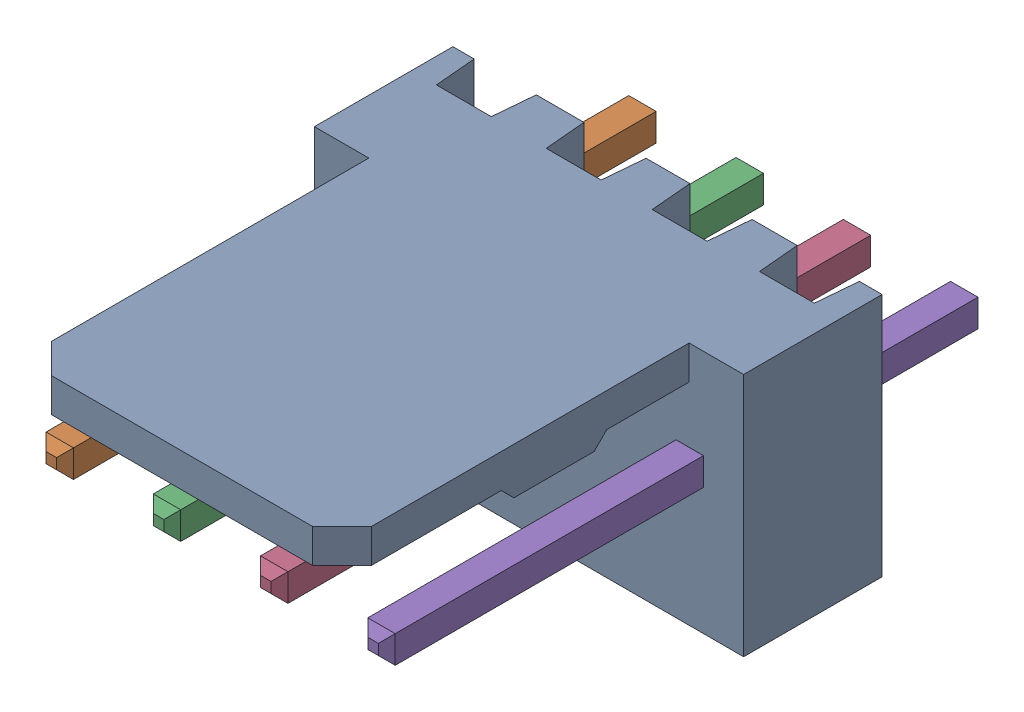
SolidWorks assembly Molex PCB 4 pin v3_3, configuration Predeterminado. Lengths in mm.
Overall size (10.16 5.79 14.92).
5 component instances, 2 part files, 0 mates.
Components (placement in the parent):
- BASE9710016-1: BASE9710016 [Predeterminado] at (2.54 2.895 -8.22) size (10.16 5.79 11.5)
- PINO9710016-1: PINO9710016 [Predeterminado] at (1.27 3.325 -0.72) size (0.65 0.65 14.2)
- PINO9710016-2: PINO9710016 [Predeterminado] at (3.81 3.325 -0.72) size (0.65 0.65 14.2)
- PINO9710016-3: PINO9710016 [Predeterminado] at (6.35 3.325 -0.72) size (0.65 0.65 14.2)
- PINO9710016-4: PINO9710016 [Predeterminado] at (8.89 3.325 -0.72) size (0.65 0.65 14.2)
